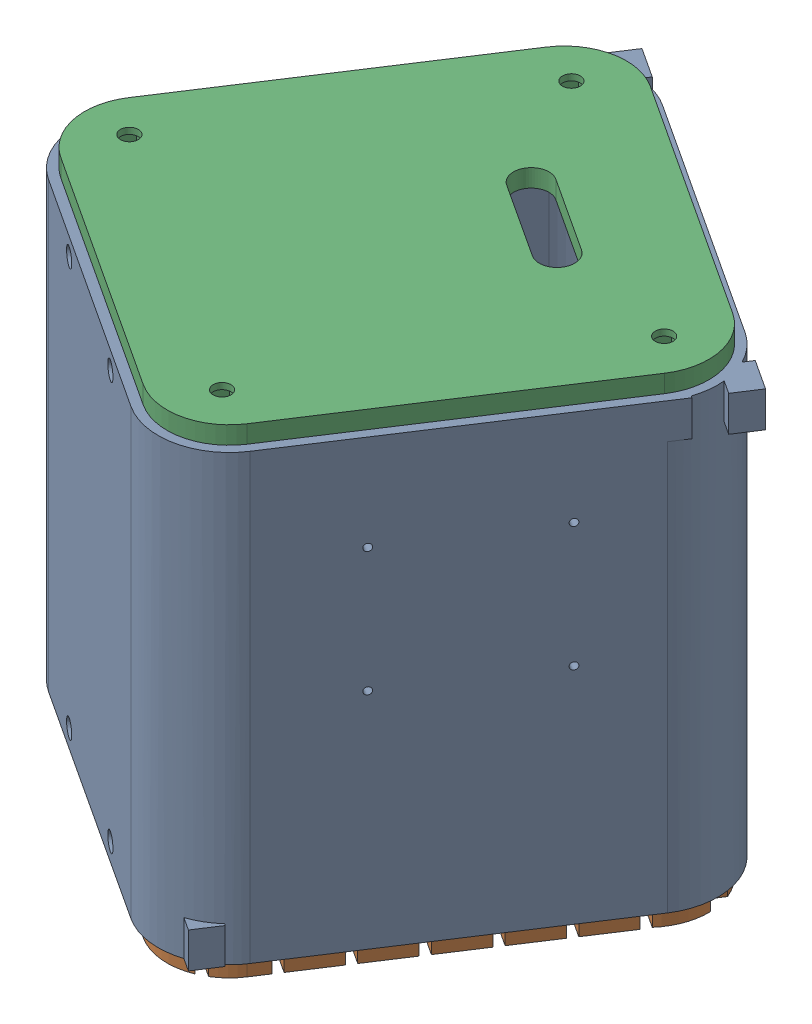
SolidWorks assembly Body, configuration Default. Lengths in mm.
Overall size (337.66 270 340.56).
3 component instances, 3 part files, 10 mates.
Components (placement in the parent):
- Body_Walls-1: Body_Walls [Default] at (294.6955 1604.4251 1117.5868) x (0.837169 0 0.546944) z (-0.546944 0 0.837169) size (240 250 250)
- Body_Bottom_New_New-1: Body_Bottom_New_New [Default] at (294.6955 1604.4251 1117.5868) x (0.837169 0 0.546944) z (-0.546944 0 0.837169) size (230 30 240)
- Body_Top_New_New-1: Body_Top_New_New [Default] at (420.4926 1854.4251 925.0379) x (0.837169 0 0.546944) z (0.546944 0 -0.837169) size (230 30 240)
Mates (geometry in assembly coordinates):
- Concentric1: concentric aligned: circle of Body_Walls-1; circle of Body_Bottom_New_New-1
- Concentric2: concentric anti-aligned: circle of Body_Walls-1; circle of Body_Bottom_New_New-1
- Concentric3: concentric aligned: circle of Body_Walls-1; circle of Body_Bottom_New_New-1
- Concentric4: concentric anti-aligned: circle of Body_Walls-1; circle of Body_Bottom_New_New-1
- Coincident5: coincident anti-aligned: plane of Body_Walls-1 through (445.6077 1854.4251 941.4462) normal (-0.546944 0 0.837169); plane of Body_Bottom_New_New-1 through (420.4926 1624.4251 925.0379) normal (0.546944 0 -0.837169)
- Concentric5: concentric anti-aligned: circle of Body_Walls-1; circle of Body_Top_New_New-1
- Concentric6: concentric anti-aligned: circle of Body_Walls-1; circle of Body_Top_New_New-1
- Concentric7: concentric anti-aligned: circle of Body_Walls-1; circle of Body_Top_New_New-1
- Concentric8: concentric aligned: circle of Body_Walls-1; circle of Body_Top_New_New-1
- Coincident10: coincident anti-aligned: plane of Body_Walls-1 through (445.6077 1854.4251 941.4462) normal (-0.546944 0 0.837169); plane of Body_Top_New_New-1 through (420.4926 1834.4251 925.0379) normal (0.546944 0 -0.837169)
